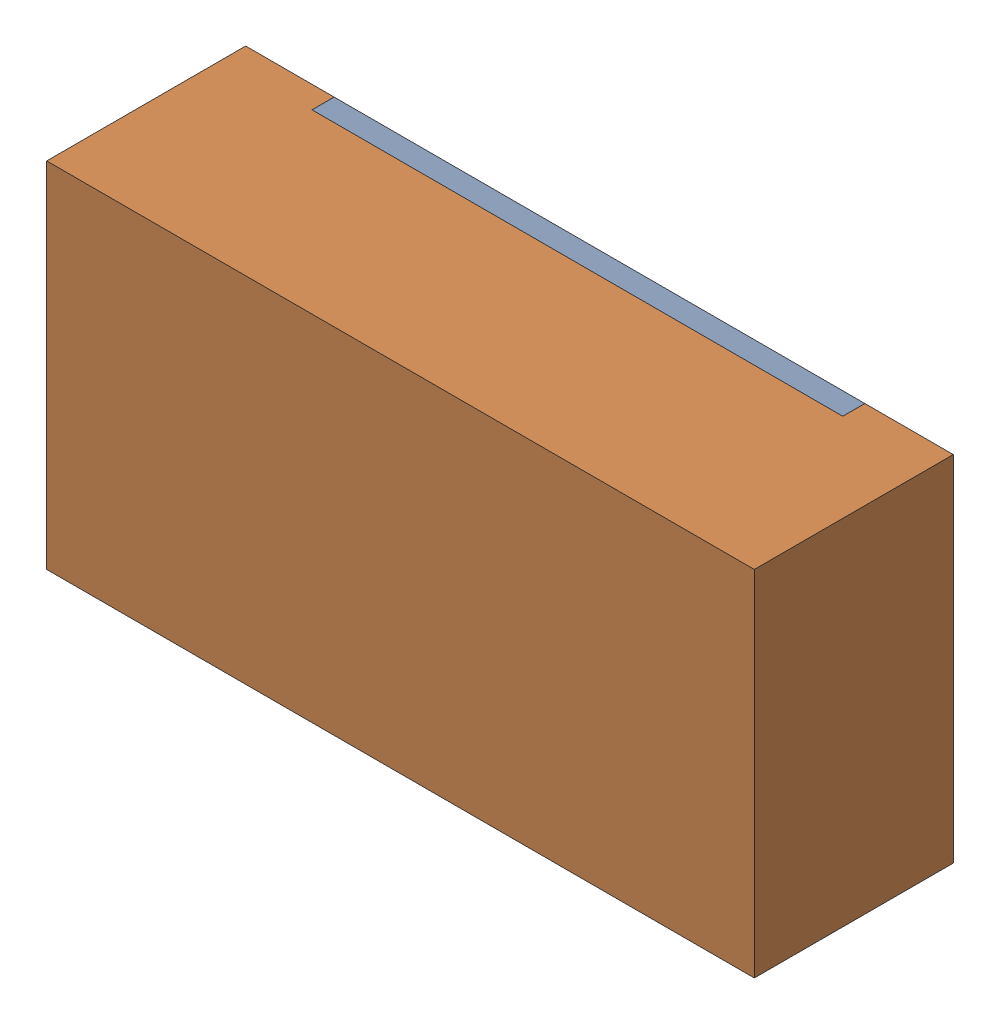
SolidWorks assembly RC4, configuration 默认. Lengths in mm.
Overall size (1.6 0.8 0.45).
3 component instances, 2 part files, 0 mates.
Components (placement in the parent):
- RC4-subassembly-1-1: RC4-subassembly-1 [默认] at (20.0659 12.3191 -1.6914) x (-1 0 0) z (0 0 -1) size (1.6 0.8 0.45)
  - R0603-1: R0603 [默认] at origin size (1.2 0.8 0.05)
  - R0603-1-1: R0603-1 [默认] at origin size (1.6 0.8 0.45)
